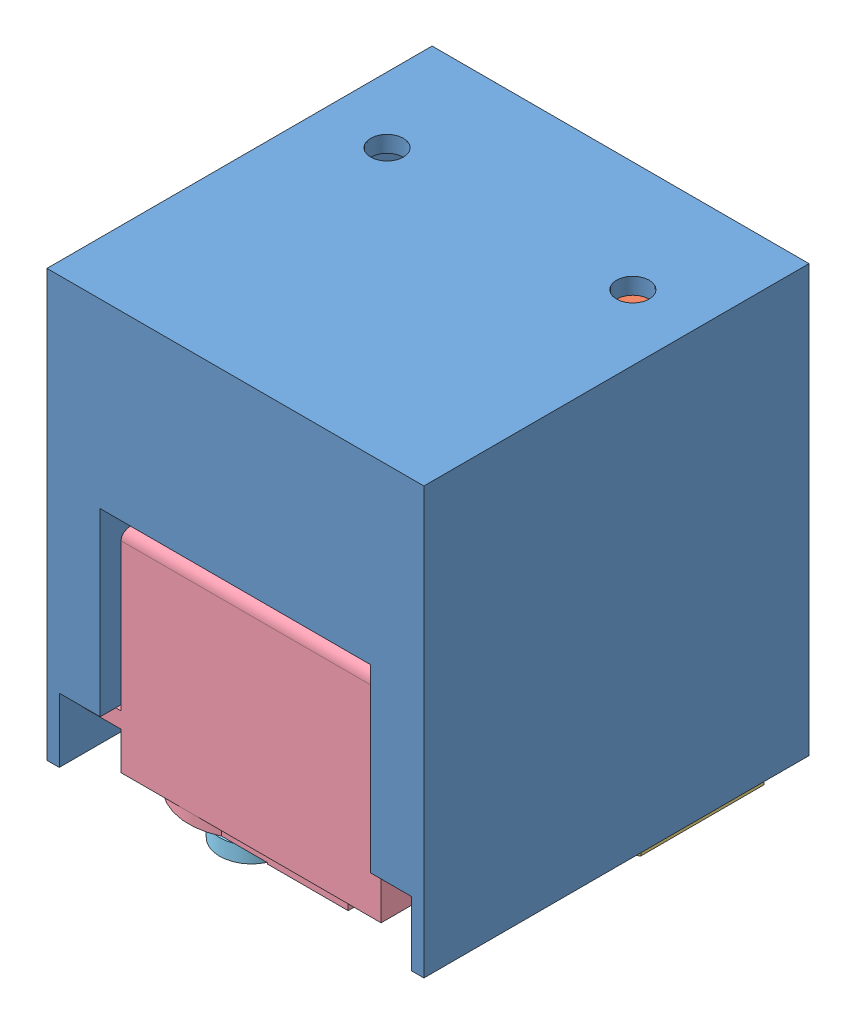
SolidWorks assembly Marker, configuration Default. Lengths in mm.
Overall size (58.42 72.74 59.69).
6 component instances, 5 part files, 10 mates.
Components (placement in the parent):
- Marker Enclosure-1: Marker Enclosure [Default] at (18.8235 10.8767 46.797) size (58.42 66.04 59.69)
- Marker Rocket Shape-1: Marker Rocket Shape [Default] at (31.3244 68.902 46.9254) x (0.304034 -0.006158 -0.952641) z (0.952583 -0.01088 0.304085) size (20.64 59.69 20.32)
- Marker Rocket Shape-2: Marker Rocket Shape [Default] at (7.3515 68.8162 47.6038) x (0.999534 -0.030486 -0.001804) z (0.000405 -0.045837 0.998949) size (20.64 59.69 20.32)
- Servo Horn-1: Servo Horn [Default] at (18.8832 6.6767 63.7574) x (-1 0 0.000786) z (0.000786 0 1) size (50.8 2.54 30.86)
- Standard Servo-1: Standard Servo [Default] at (20.3268 47.9167 78.7353) x (-1 0 0) z (0 0 1) size (53.74 42.63 19.57)
- Servo Arm-1: Servo Arm [Default] at (18.8714 4.1767 48.7574) x (0.323809 0 -0.946122) z (0.946122 0 0.323809) size (37.5 4.5 10)
Mates (geometry in assembly coordinates):
- Coincident2: coincident anti-aligned: point of Marker Rocket Shape-2; plane of Servo Horn-1 through (18.8832 9.2167 63.7574) normal (0 1 0)
- Coincident3: coincident anti-aligned: point of Marker Rocket Shape-1; plane of Servo Horn-1 through (18.8832 9.2167 63.7574) normal (0 1 0)
- Concentric2: concentric anti-aligned: cylinder of Standard Servo-1 through (9.1572 12.3167 77.1411) axis (0 -1 0) radius 1.27; cylinder of Servo Arm-1 through (9.1572 4.1767 77.1411) axis (0 1 0) radius 1.5
- Coincident5: coincident anti-aligned: plane of Standard Servo-1 through (9.1572 8.6767 77.1411) normal (0 -1 0); circle of Servo Arm-1
- Concentric3: concentric: cylinder of Servo Arm-1 through (15.6333 6.6767 58.2186) axis (0 -1 0) radius 1; cylinder of Servo Horn-1 through (15.6333 9.2167 58.2186) axis (0 -1 0) radius 1.27
- Coincident6: coincident anti-aligned: plane of Servo Arm-1 through (18.8714 6.6767 48.7574) normal (0 1 0); plane of Servo Horn-1 through (18.8832 6.6767 63.7574) normal (0 -1 0)
- Width1: width aligned: plane of Marker Enclosure-1 through (-8.4815 20.8561 64.9402) normal (0 0 1); plane of Marker Enclosure-1 through (18.8235 74.3767 89.342) normal (0 0 1); plane of Standard Servo-1 through (38.9835 12.5467 86.9261) normal (0 0 1); plane of Standard Servo-1 through (38.9835 12.5467 67.3561) normal (0 0 -1)
- Width2: width aligned: plane of Marker Enclosure-1 through (-8.4815 20.8561 85.7682) normal (1 0 0); plane of Marker Enclosure-1 through (46.1285 20.8561 85.7682) normal (-1 0 0); plane of Standard Servo-1 through (38.9835 12.5467 67.3561) normal (1 0 0); plane of Standard Servo-1 through (-1.3365 12.5467 67.3561) normal (-1 0 0)
- Coincident8: coincident aligned: plane of Marker Enclosure-1 through (18.8235 10.8767 46.797) normal (0 -1 0); plane of Standard Servo-1 through (9.1572 10.8767 77.1411) normal (0 -1 0)
- Lock1: lock: unknown of Servo Horn-1; unknown of Servo Arm-1
